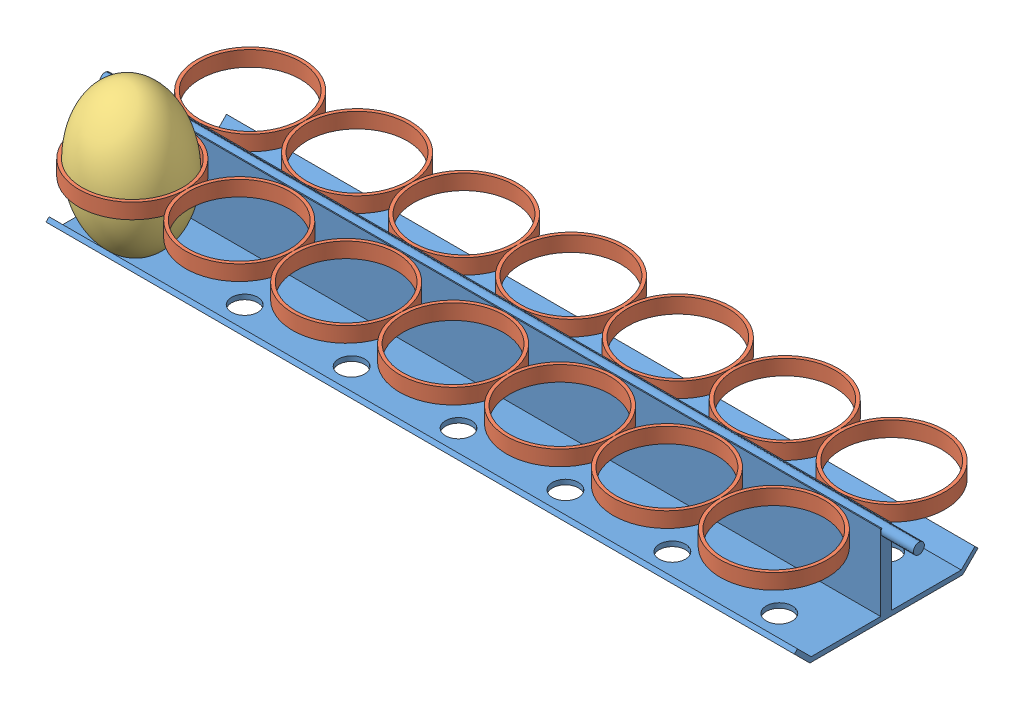
SolidWorks assembly lapghep1danmoi, configuration Default. Lengths in mm.
Overall size (373 71.36 109.63).
18 component instances, 3 part files, 9 mates.
Components (placement in the parent):
- trucchinhmoi-1: trucchinhmoi [Default] at (148.5794 210.732 335.0874) size (373 38 84.14)
- lapghepmoi-1: lapghepmoi [Default] at (199.6763 214.875 314.9312) size (343 7 49)
  - 1oluoi-1: 1oluoi [Default] at (-2.097 23.8571 47.1563) size (49 7 49)
  - 1oluoi-2: 1oluoi [Default] at (46.903 23.8571 47.1563) size (49 7 49)
  - 1oluoi-3: 1oluoi [Default] at (-51.097 23.8571 47.1563) size (49 7 49)
  - 1oluoi-4: 1oluoi [Default] at (-100.097 23.8571 47.1563) size (49 7 49)
  - 1oluoi-5: 1oluoi [Default] at (95.903 23.8571 47.1563) size (49 7 49)
  - 1oluoi-6: 1oluoi [Default] at (-149.097 23.8571 47.1563) size (49 7 49)
  - 1oluoi-7: 1oluoi [Default] at (-198.097 23.8571 47.1563) size (49 7 49)
- lapghepmoi-2: lapghepmoi [Default] at (199.6763 214.875 260.9312) size (343 7 49)
  - 1oluoi-1: 1oluoi [Default] at (-2.097 23.8571 47.1563) size (49 7 49)
  - 1oluoi-2: 1oluoi [Default] at (46.903 23.8571 47.1563) size (49 7 49)
  - 1oluoi-3: 1oluoi [Default] at (-51.097 23.8571 47.1563) size (49 7 49)
  - 1oluoi-4: 1oluoi [Default] at (-100.097 23.8571 47.1563) size (49 7 49)
  - 1oluoi-5: 1oluoi [Default] at (95.903 23.8571 47.1563) size (49 7 49)
  - 1oluoi-6: 1oluoi [Default] at (-149.097 23.8571 47.1563) size (49 7 49)
  - 1oluoi-7: 1oluoi [Default] at (-198.097 23.8571 47.1563) size (49 7 49)
- trungga-1: trungga [Default] at (1.586 243.3071 362.5857) x (-0.880436 -0.105529 0.462274) z (-0.46012 -0.045387 -0.886696) size (45 65 45)
Mates (geometry in assembly coordinates):
- Tangent1: tangent anti-aligned: plane of trucchinhmoi-1 through (-47.4206 245.732 337.5874) normal (0 0 1); cylinder of ? through (320.0794 245.732 362.0874) axis (0 -1 0) radius 24.5
- Tangent2: tangent anti-aligned: plane of trucchinhmoi-1 through (-22.9206 245.732 337.5874) normal (0 0 1); cylinder of lapghepmoi-1/1oluoi-7 through (1.5794 245.732 362.0874) axis (0 -1 0) radius 24.5
- Tangent3: tangent aligned: plane of trucchinhmoi-1 through (-22.9206 245.732 337.5874) normal (-1 0 0); cylinder of lapghepmoi-1/1oluoi-7 through (1.5794 245.732 362.0874) axis (0 -1 0) radius 24.5
- Coincident1: coincident aligned: plane of trucchinhmoi-1 through (148.5794 245.732 335.0874) normal (0 1 0); plane of lapghepmoi-1/1oluoi-6 through (50.5794 245.732 362.0874) normal (0 1 0)
- Tangent4: tangent anti-aligned: plane of trucchinhmoi-1 through (-22.9206 245.732 332.5874) normal (0 0 -1); cylinder of lapghepmoi-2/1oluoi-7 through (1.5794 245.732 308.0874) axis (0 -1 0) radius 24.5
- Tangent5: tangent aligned: plane of trucchinhmoi-1 through (-22.9206 245.732 337.5874) normal (-1 0 0); cylinder of lapghepmoi-2/1oluoi-7 through (1.5794 245.732 308.0874) axis (0 -1 0) radius 24.5
- Tangent6: tangent anti-aligned: plane of trucchinhmoi-1 through (-47.4206 245.732 332.5874) normal (0 0 -1); cylinder of ? through (320.0794 245.732 308.0874) axis (0 -1 0) radius 24.5
- Coincident2: coincident aligned: plane of trucchinhmoi-1 through (148.5794 245.732 335.0874) normal (0 1 0); plane of lapghepmoi-2/1oluoi-5 through (295.5794 245.732 308.0874) normal (0 1 0)
- Tangent10: tangent: cylinder of lapghepmoi-1/1oluoi-7 through (1.5794 245.732 362.0874) axis (0 -1 0) radius 23; face of trungga-1
